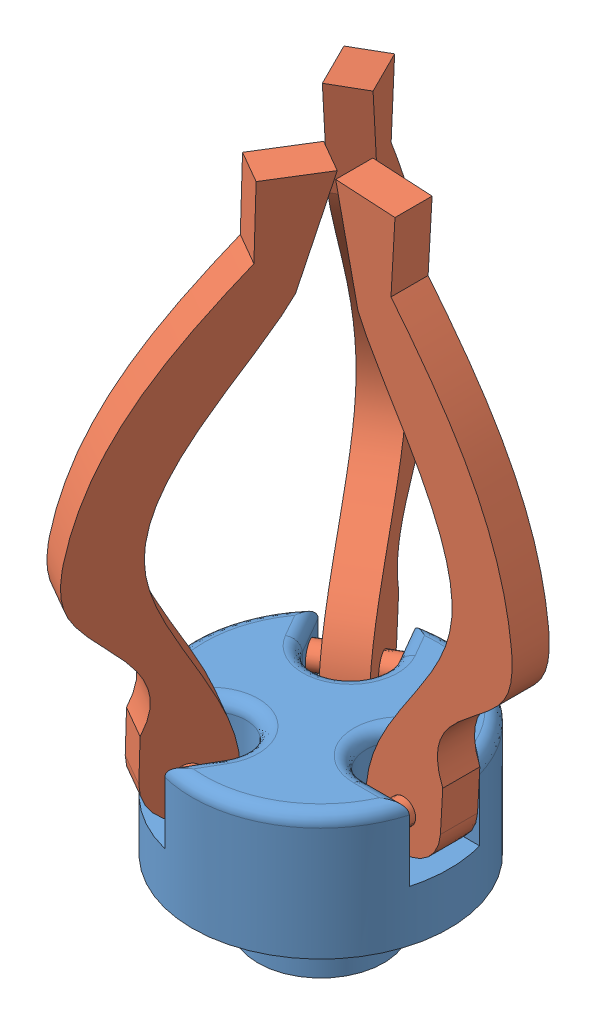
SolidWorks assembly Gripper, configuration Default. Lengths in mm.
Overall size (161.06 273.54 180.78).
4 component instances, 2 part files, 3 mates.
Components (placement in the parent):
- Gripper-1: Gripper [Default] at (40.1703 45.6976 67.3583) size (103.88 76.7 103.88)
- Gripper_Hands-1: Gripper_Hands [Default] at (19.7446 85.0966 102.7336) x (-0.499869 0.022913 0.865798) z (-0.866025 0 -0.5) size (78.87 220.37 34.4)
- Gripper_Hands-2: Gripper_Hands [Default] at (19.7472 85.0966 31.9814) x (-0.4955 -0.133859 -0.858232) z (0.866025 0 -0.5) size (78.87 220.37 34.4)
- Gripper_Hands-3: Gripper_Hands [Default] at (81.0191 85.0966 67.3597) x (0.998404 -0.056471 0) z (0 0 1) size (78.87 220.37 34.4)
Mates (geometry in assembly coordinates):
- ProfileCenter1: profile center aligned: plane of Gripper_Hands-2 through (4.8515 85.0966 40.5814) normal (-0.866025 0 0.5); circle of Gripper-1
- ProfileCenter2: profile center aligned: plane of Gripper_Hands-3 through (81.0191 85.0966 50.1597) normal (0 0 -1); plane of Gripper-1 through (81.0191 85.0966 50.1597) normal (0 0 1)
- ProfileCenter3: profile center aligned: plane of Gripper_Hands-1 through (34.6402 85.0966 111.3336) normal (0.866025 0 0.5); plane of Gripper-1 through (34.6402 85.0966 111.3336) normal (-0.866025 0 -0.5)
